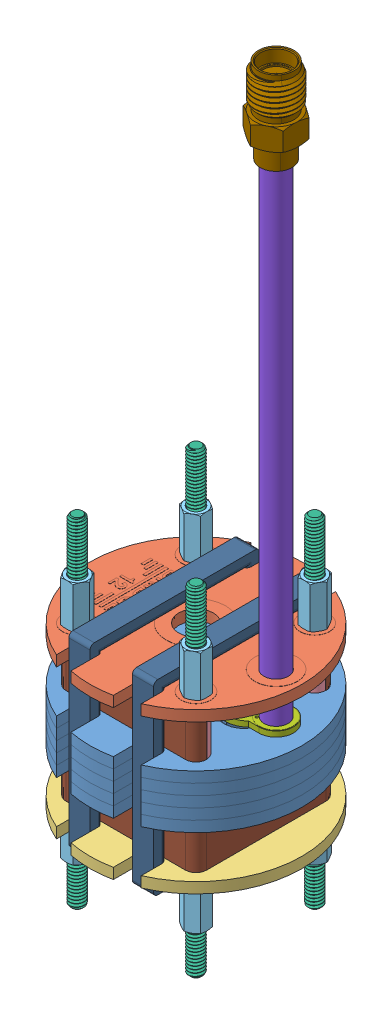
SolidWorks assembly 122001556, configuration Default. Lengths in mm.
Overall size (32.96 115.97 31.75).
36 component instances, 11 part files, 10 mates.
Components (placement in the parent):
- 122001547-1: 122001547 [Default] at origin size (32.96 115.97 31.75)
  - 121003116-1: 121003116 [Default] at origin size (31.75 1.6 31.75)
  - 121003116-4: 121003116 [Default] at (0 -1.6 0) size (31.75 1.6 31.75)
  - 121003116-7: 121003116 [Default] at (0 -3.2 0) size (31.75 1.6 31.75)
  - 121003117-1: 121003117 [Default] at (0 11.15 0) size (31.75 1.63 31.75)
  - 121003118-1: 121003118 [Default] at (0 -11.15 0) size (31.75 1.63 31.75)
  - 92511A129-1: 92511A129 [92511A129] at (8.89 7.175 -8.89) x (0.864839 0 -0.502049) z (0 -1 0) size (3.17 3.17 6.35)
  - 91780A023-1: 91780A023 [91780A023] at (8.89 -15.125 8.89) x (1 0 0) z (0 -1 0) size (3.17 3.67 6.66)
  - 91780A023-2: 91780A023 [91780A023] at (-8.89 -15.125 8.89) x (0 0 1) z (0 -1 0) size (3.17 3.67 6.66)
  - 91780A023-3: 91780A023 [91780A023] at (-8.89 -15.125 -8.89) x (-1 0 0) z (0 -1 0) size (3.17 3.67 6.66)
  - 91780A023-4: 91780A023 [91780A023] at (8.89 -15.125 -8.89) x (0 0 -1) z (0 -1 0) size (3.17 3.67 6.66)
  - 93225A413-1: 93225A413 [93225A413] at (8.89 0.75 8.89) x (0 -1 0) z (0 0 1) size (51.63 2.21 2.52)
  - 93225A413-2: 93225A413 [93225A413] at (-8.89 0.75 8.89) x (0 -1 0) z (-1 0 0) size (51.63 2.21 2.52)
  - 93225A413-3: 93225A413 [93225A413] at (-8.89 0.75 -8.89) x (0 -1 0) z (0 0 -1) size (51.63 2.21 2.52)
  - 93225A413-4: 93225A413 [93225A413] at (8.89 0.75 -8.89) x (0 -1 0) z (1 0 0) size (51.63 2.21 2.52)
  - 122001546-1: 122001546 [Default] at (12 5 0) x (0 0 -1) z (1 0 0) size (10.16 86.37 12.68)
    - 121003119-1: 121003119 [Default] at origin size (7.2 0.85 10.2)
    - 121003122-1: 121003122 [Default] at (0 0.8254 0) x (0.731519 0 0.681822) z (-0.681822 0 0.731519) size (3.58 77.47 3.58)
    - 901-9704-1: 901-9704 [Default] at (0 73.2154 0) x (0 1 0) z (-0.546944 0 0.837169) size (12.71 7.34 7.34)
  - 121003116-10: 121003116 [Default] at (0 1.6 0) size (31.75 1.6 31.75)
  - 121003116-11: 121003116 [Default] at (0 3.2 0) size (31.75 1.6 31.75)
  - 92511A129-9: 92511A129 [92511A129] at (8.89 7.175 8.89) x (0.502049 0 0.864839) z (0 -1 0) size (3.17 3.17 6.35)
  - 92511A129-10: 92511A129 [92511A129] at (-8.89 7.175 8.89) x (-0.864839 0 0.502049) z (0 -1 0) size (3.17 3.17 6.35)
  - 92511A129-11: 92511A129 [92511A129] at (-8.89 7.175 -8.89) x (-0.502049 0 -0.864839) z (0 -1 0) size (3.17 3.17 6.35)
  - 92511A129-12: 92511A129 [92511A129] at (8.89 -7.175 -8.89) x (0.864839 0 -0.502049) z (0 -1 0) size (3.17 3.17 6.35)
  - 92511A129-13: 92511A129 [92511A129] at (-8.89 -7.175 -8.89) x (-0.502049 0 -0.864839) z (0 -1 0) size (3.17 3.17 6.35)
  - 92511A129-14: 92511A129 [92511A129] at (8.89 -7.175 8.89) x (0.502049 0 0.864839) z (0 -1 0) size (3.17 3.17 6.35)
  - 92511A129-15: 92511A129 [92511A129] at (-8.89 -7.175 8.89) x (-0.864839 0 0.502049) z (0 -1 0) size (3.17 3.17 6.35)
  - 91780A023-5: 91780A023 [91780A023] at (8.89 15.125 8.89) x (1 0 0) z (0 1 0) size (3.17 3.67 6.66)
  - 91780A023-6: 91780A023 [91780A023] at (-8.89 15.125 -8.89) x (-1 0 0) z (0 1 0) size (3.17 3.67 6.66)
  - 91780A023-7: 91780A023 [91780A023] at (8.89 15.125 -8.89) x (0 0 1) z (0 1 0) size (3.17 3.67 6.66)
  - 91780A023-8: 91780A023 [91780A023] at (-8.89 15.125 8.89) x (0 0 -1) z (0 1 0) size (3.17 3.67 6.66)
- 121003138-1: 121003138 [Default] at (-6.35 -0.115 0) x (0 0 -1) z (1 0 0) size (25.4 27.94 3.17)
- 121003139-1: 121003139 [COUPLING LOOP SIDE] at (0 4 0) x (0 0 -1) z (1 0 0) size (21.06 6.35 21.06)
- 121003139-2: 121003139 [Default] at (0 -10.35 0) size (21.06 6.35 21.06)
- 121003138-2: 121003138 [Default] at (3.175 -0.115 0) x (0 0 -1) z (1 0 0) size (25.4 27.94 3.17)
Mates (geometry in assembly coordinates):
- Coincident14: coincident anti-aligned: plane of 122001547-1/121003117-1 through (-5.715 11.95 10.795) normal (0 0 1); plane of 121003138-1 through (-3.175 -12.18 10.795) normal (0 0 -1)
- Coincident15: coincident anti-aligned: plane of 122001547-1/121003117-1 through (-3.175 11.95 11.43) normal (-1 0 0); plane of 121003138-1 through (-3.175 -0.115 0) normal (1 0 0)
- Coincident16: coincident anti-aligned: plane of 122001547-1/121003117-1 through (0 11.95 0) normal (0 1 0); plane of 121003138-1 through (-3.175 11.95 10.795) normal (0 -1 0)
- Coincident17: coincident anti-aligned: plane of 122001547-1/121003116-11 through (0 4 0) normal (0 1 0); plane of 121003139-1 through (8.9408 4 8.9408) normal (0 -1 0)
- Concentric19: concentric anti-aligned: cylinder of 122001547-1/92511A129-9 through (8.89 4 8.89) axis (0 1 0) radius 1.5875; cylinder of 121003139-1 through (8.89 10.35 8.89) axis (0 -1 0) radius 1.5875
- Concentric20: concentric anti-aligned: cylinder of 122001547-1/92511A129-1 through (8.89 4 -8.89) axis (0 1 0) radius 1.5875; cylinder of 121003139-1 through (8.89 10.35 -8.89) axis (0 -1 0) radius 1.5875
- Concentric21: concentric anti-aligned: cylinder of 122001547-1/92511A129-15 through (-8.89 -10.35 8.89) axis (0 1 0) radius 1.5875; cylinder of 121003139-2 through (-8.89 -4 8.89) axis (0 -1 0) radius 1.5875
- Concentric22: concentric aligned: line of 122001547-1/93225A413-1 through (8.89 25.8098 8.89) axis (0 -1 0); cylinder of 121003139-2 through (8.89 -4 8.89) axis (0 -1 0) radius 1.5875
- Coincident18: coincident anti-aligned: plane of 122001547-1/121003116-7 through (0 -4 0) normal (0 -1 0); plane of 121003139-2 through (-8.9408 -4 8.9408) normal (0 1 0)
- Coincident19: coordinate: point of 122001547-1
